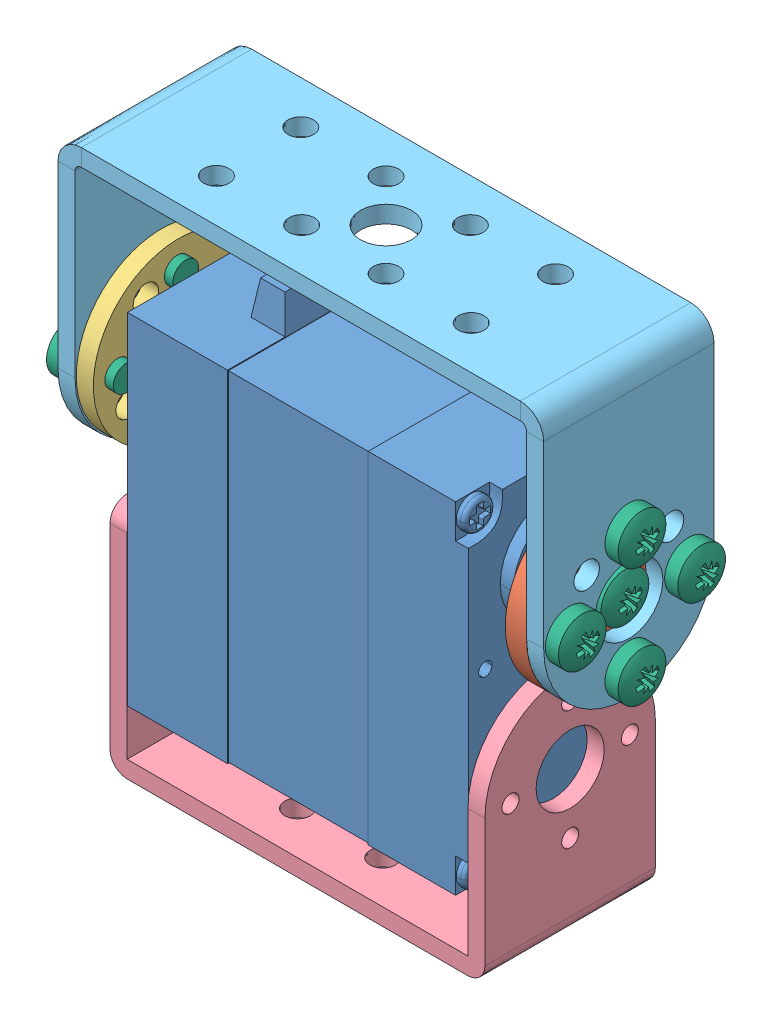
SolidWorks assembly 宽窄u, configuration 默认. Lengths in mm.
Overall size (61.71 61.6 27.69).
14 component instances, 6 part files, 25 mates.
Components (placement in the parent):
- 双轴舵机-1: 双轴舵机 [默认] at (-45.4074 -5.3004 41) size (51 44 20)
- 金属主舵盘-1: 金属主舵盘 [默认] at (-18.4074 5.1007 51.1556) x (0 -0.011366 0.999935) z (0 -0.999935 -0.011366) size (20 4.5 20)
- 金属从舵盘-1: 金属从舵盘 [默认] at (-71.4074 5.1996 51) x (0 -0.547347 0.836906) z (1 0 0) size (20 20 3)
- 窄U支架-1: 窄U支架 [默认] at (-45.4074 -32.7004 51.0424) x (-1 0 0) z (0 0.000041 -1) size (44 27 20)
- 宽U支架-1: 宽U支架 [默认] at (-59.3279 18.0464 61.1556) x (1 0 0) z (0 0 -1) size (57 33.8 20)
- cross recessed pan head screws gb-1: cross recessed pan head screws gb [GB_CROSS_SCREWS_TYPE1 M3X5-5  Z type-N] at (-75.8074 12.1007 51.1556) size (7.35 5.6 5.6)
- cross recessed pan head screws gb-2: cross recessed pan head screws gb [GB_CROSS_SCREWS_TYPE1 M3X5-5  Z type-N] at (-75.8074 5.1007 58.1556) size (7.35 5.6 5.6)
- cross recessed pan head screws gb-3: cross recessed pan head screws gb [GB_CROSS_SCREWS_TYPE1 M3X5-5  Z type-N] at (-75.8074 5.1007 44.1556) size (7.35 5.6 5.6)
- cross recessed pan head screws gb-4: cross recessed pan head screws gb [GB_CROSS_SCREWS_TYPE1 M3X5-5  Z type-N] at (-75.8074 -1.8993 51.1556) size (7.35 5.6 5.6)
- cross recessed pan head screws gb-5: cross recessed pan head screws gb [GB_CROSS_SCREWS_TYPE1 M3X5-5  Z type-N] at (-14.0074 12.1007 51.1556) x (-1 0 0) z (0 -0.924225 -0.381849) size (7.35 5.6 5.6)
- cross recessed pan head screws gb-6: cross recessed pan head screws gb [GB_CROSS_SCREWS_TYPE1 M3X5-5  Z type-N] at (-14.0074 5.1007 44.1556) x (-1 0 0) z (0 -0.924225 -0.381849) size (7.35 5.6 5.6)
- cross recessed pan head screws gb-7: cross recessed pan head screws gb [GB_CROSS_SCREWS_TYPE1 M3X5-5  Z type-N] at (-14.0074 5.1007 58.1556) x (-1 0 0) z (0 -0.924225 -0.381849) size (7.35 5.6 5.6)
- cross recessed pan head screws gb-8: cross recessed pan head screws gb [GB_CROSS_SCREWS_TYPE1 M3X5-5  Z type-N] at (-14.0074 -1.8993 51.1556) x (-1 0 0) z (0 -0.924225 -0.381849) size (7.35 5.6 5.6)
- cross recessed pan head screws gb-9: cross recessed pan head screws gb [GB_CROSS_SCREWS_TYPE1 M3X5-5  Z type-N] at (-16.0074 5.1007 51.1556) x (-1 0 0) z (0 -0.924225 -0.381849) size (7.35 5.6 5.6)
Mates (geometry in assembly coordinates):
- 重合15: coincident anti-aligned: plane of 双轴舵机-1 through (-19.9074 6.2313 50.1505) normal (1 0 0); plane of 金属主舵盘-1 through (-19.9074 5.1007 51.1556) normal (-1 0 0)
- 同心18: concentric anti-aligned: cylinder of 双轴舵机-1 through (-23.9074 5.1007 51.1556) axis (1 0 0) radius 1.5; cylinder of 金属主舵盘-1 through (-18.4074 5.1007 51.1556) axis (-1 0 0) radius 1.5
- 同心19: concentric anti-aligned: cylinder of 双轴舵机-1 through (-66.9074 5.1996 51) axis (-1 0 0) radius 1.5; cylinder of 金属从舵盘-1 through (-71.4074 5.1996 51) axis (1 0 0) radius 3
- 重合16: coincident anti-aligned: plane of 金属主舵盘-1 through (-18.4074 5.1007 51.1556) normal (1 0 0); plane of 宽U支架-1 through (-18.4074 26.9007 41.1556) normal (-1 0 0)
- 同心20: concentric aligned: cylinder of 金属主舵盘-1 through (-18.4074 5.1007 51.1556) axis (-1 0 0) radius 1.5; cylinder of 宽U支架-1 through (-16.4074 5.1007 51.1556) axis (-1 0 0) radius 4
- 重合17: coincident anti-aligned: plane of 金属从舵盘-1 through (-71.4074 5.1996 51) normal (-1 0 0); plane of 宽U支架-1 through (-71.4074 5.1007 41.1556) normal (1 0 0)
- 平行8: parallel anti-aligned: line of 双轴舵机-1 through (-25.4074 -21.3004 61) axis (0 1 0); line of 宽U支架-1 through (-16.4074 26.1641 61.1556) axis (0 -1 0)
- 重合19: coincident anti-aligned: plane of 宽U支架-1 through (-73.4074 5.1007 41.1556) normal (-1 0 0); plane of GB_CROSS_SCREWS_TYPE1 M3X5-5  Z type-N-1 through (-73.4074 13.9007 51.1556) normal (1 0 0)
- 重合20: coincident anti-aligned: circle of 宽U支架-1; cylinder of GB_CROSS_SCREWS_TYPE1 M3X5-5  Z type-N-1 through (-71.2916 12.1007 51.1556) axis (1 0 0) radius 1.5
- 重合21: coincident anti-aligned: plane of 宽U支架-1 through (-73.4074 5.1007 41.1556) normal (-1 0 0); plane of GB_CROSS_SCREWS_TYPE1 M3X5-5  Z type-N-2 through (-73.4074 6.9007 58.1556) normal (1 0 0)
- 同心22: concentric anti-aligned: cylinder of 宽U支架-1 through (-16.4074 5.1007 58.1556) axis (-1 0 0) radius 1.5; cylinder of GB_CROSS_SCREWS_TYPE1 M3X5-5  Z type-N-2 through (-71.2916 5.1007 58.1556) axis (1 0 0) radius 1.5
- 重合22: coincident anti-aligned: plane of 宽U支架-1 through (-73.4074 5.1007 41.1556) normal (-1 0 0); plane of GB_CROSS_SCREWS_TYPE1 M3X5-5  Z type-N-3 through (-73.4074 6.9007 44.1556) normal (1 0 0)
- 同心23: concentric anti-aligned: cylinder of 宽U支架-1 through (-16.4074 5.1007 44.1556) axis (-1 0 0) radius 1.5; cylinder of GB_CROSS_SCREWS_TYPE1 M3X5-5  Z type-N-3 through (-71.2916 5.1007 44.1556) axis (1 0 0) radius 1.5
- 重合23: coincident anti-aligned: plane of 宽U支架-1 through (-73.4074 5.1007 41.1556) normal (-1 0 0); plane of GB_CROSS_SCREWS_TYPE1 M3X5-5  Z type-N-4 through (-73.4074 -0.0993 51.1556) normal (1 0 0)
- 同心24: concentric anti-aligned: cylinder of 宽U支架-1 through (-16.4074 -1.8993 51.1556) axis (-1 0 0) radius 1.5; cylinder of GB_CROSS_SCREWS_TYPE1 M3X5-5  Z type-N-4 through (-71.2916 -1.8993 51.1556) axis (1 0 0) radius 1.5
- 重合24: coincident anti-aligned: plane of 宽U支架-1 through (-16.4074 26.9007 41.1556) normal (1 0 0); plane of GB_CROSS_SCREWS_TYPE1 M3X5-5  Z type-N-5 through (-16.4074 12.788 49.492) normal (-1 0 0)
- 同心25: concentric aligned: cylinder of 宽U支架-1 through (-16.4074 12.1007 51.1556) axis (-1 0 0) radius 1.5; cylinder of GB_CROSS_SCREWS_TYPE1 M3X5-5  Z type-N-5 through (-18.5232 12.1007 51.1556) axis (-1 0 0) radius 1.5
- 重合25: coincident anti-aligned: plane of 宽U支架-1 through (-16.4074 26.9007 41.1556) normal (1 0 0); plane of GB_CROSS_SCREWS_TYPE1 M3X5-5  Z type-N-6 through (-16.4074 5.788 42.492) normal (-1 0 0)
- 同心26: concentric aligned: cylinder of 宽U支架-1 through (-16.4074 5.1007 44.1556) axis (-1 0 0) radius 1.5; cylinder of GB_CROSS_SCREWS_TYPE1 M3X5-5  Z type-N-6 through (-18.5232 5.1007 44.1556) axis (-1 0 0) radius 1.5
- 重合26: coincident anti-aligned: plane of 宽U支架-1 through (-16.4074 26.9007 41.1556) normal (1 0 0); plane of GB_CROSS_SCREWS_TYPE1 M3X5-5  Z type-N-7 through (-16.4074 5.788 56.492) normal (-1 0 0)
- 同心27: concentric aligned: cylinder of 宽U支架-1 through (-16.4074 5.1007 58.1556) axis (-1 0 0) radius 1.5; cylinder of GB_CROSS_SCREWS_TYPE1 M3X5-5  Z type-N-7 through (-18.5232 5.1007 58.1556) axis (-1 0 0) radius 1.5
- 重合27: coincident anti-aligned: plane of 宽U支架-1 through (-16.4074 26.9007 41.1556) normal (1 0 0); plane of GB_CROSS_SCREWS_TYPE1 M3X5-5  Z type-N-8 through (-16.4074 -1.212 49.492) normal (-1 0 0)
- 同心28: concentric aligned: cylinder of 宽U支架-1 through (-16.4074 -1.8993 51.1556) axis (-1 0 0) radius 1.5; cylinder of GB_CROSS_SCREWS_TYPE1 M3X5-5  Z type-N-8 through (-18.5232 -1.8993 51.1556) axis (-1 0 0) radius 1.5
- 重合28: coincident anti-aligned: plane of 金属主舵盘-1 through (-18.4074 5.1007 51.1556) normal (1 0 0); plane of GB_CROSS_SCREWS_TYPE1 M3X5-5  Z type-N-9 through (-18.4074 5.788 49.492) normal (-1 0 0)
- 同心29: concentric aligned: cylinder of 金属主舵盘-1 through (-18.4074 5.1007 51.1556) axis (-1 0 0) radius 1.5; cylinder of GB_CROSS_SCREWS_TYPE1 M3X5-5  Z type-N-9 through (-20.5232 5.1007 51.1556) axis (-1 0 0) radius 1.5
